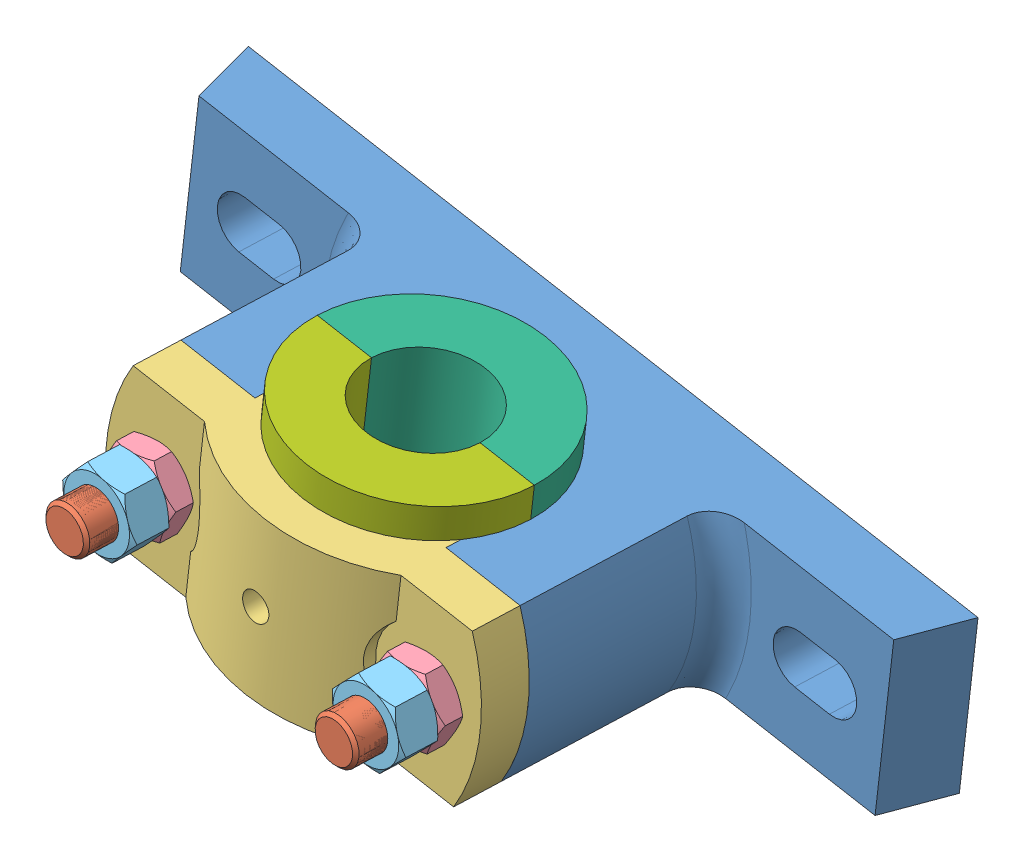
SolidWorks assembly PB, configuration Default. Lengths in mm.
Overall size (173.45 57.22 90.27).
10 component instances, 7 part files, 27 mates.
Components (placement in the parent):
- Body-PB-1: Body-PB [Default] at (22.8033 -109.1486 105.9036) x (-0.991123 0.125842 -0.042895) z (0.125431 0.992028 0.012142) size (168 55 36)
- Bolt-PB-1: Bolt-PB [Default] at (51.3093 -113.3846 157.5158) x (0.044081 0.006653 -0.999006) z (0.991123 -0.125842 0.042895) size (83.71 18 18)
- Cap-PB-1: Cap-PB [Default] at (18.5718 -127.303 150.4142) x (-0.991123 0.125842 -0.042895) z (0.125431 0.992028 0.012142) size (86 30 36)
- Bolt-PB-2: Bolt-PB [Default] at (-10.1402 -105.5824 154.8563) x (0.044081 0.006653 -0.999006) z (-0.125431 -0.992028 -0.012142) size (83.71 18 18)
- Lock Nut-PB-1: Lock Nut-PB [Default] at (50.6628 -113.4822 172.1687) x (0.942475 -0.33195 0.039376) z (-0.331358 -0.943273 -0.020903) size (17.57 5 17.08)
- M10-PB-1: M10-PB [Default] at (50.4424 -113.5154 177.1638) x (0.822368 -0.568026 0.032504) z (-0.567245 -0.822984 -0.030511) size (17.57 8 17.08)
- Lock Nut-PB-2: Lock Nut-PB [Default] at (-11.0072 -105.7132 174.5042) x (-0.086489 -0.996198 -0.010451) z (0.995277 -0.086863 0.043338) size (17.57 5 17.08)
- M10-PB-2: M10-PB [Default] at (-11.3599 -105.7665 182.4963) x (0.625284 -0.780076 0.022395) z (0.779152 0.625649 0.038547) size (17.57 8 17.08)
- Bearing Bottom Half-PB-2: Bearing Bottom Half-PB [Default] at (21.04 -109.4147 145.8638) x (-0.125431 -0.992028 -0.012142) z (0.044081 0.006653 -0.999006) size (50 50 25)
- Bearing Top Half-PB-2: Bearing Top Half-PB [Default] at (21.04 -109.4147 145.8638) x (-0.125431 -0.992028 -0.012142) z (-0.044081 -0.006653 0.999006) size (50 50 25)
Mates (geometry in assembly coordinates):
- Coincident8: coincident anti-aligned: plane of Body-PB-1 through (40.4547 -130.0597 149.586) normal (-0.044081 -0.006653 0.999006); plane of Cap-PB-1 through (44.9702 -94.3467 150.0231) normal (0.044081 0.006653 -0.999006)
- Coincident9: coincident anti-aligned: plane of Body-PB-1 through (-3.1547 -124.5227 147.6986) normal (-0.044081 -0.006653 0.999006); plane of Cap-PB-1 through (5.2978 -89.3095 148.3061) normal (0.044081 0.006653 -0.999006)
- Coincident10: coincident aligned: circle of Body-PB-1; circle of Cap-PB-1
- Coincident11: coincident aligned: circle of Body-PB-1; circle of Cap-PB-1
- Concentric2: concentric aligned: cylinder of Body-PB-1 through (53.1313 -113.1096 116.2244) axis (-0.044081 -0.006653 0.999006) radius 5.25; cylinder of Bolt-PB-1 through (48.6657 -113.7836 217.4295) axis (-0.044081 -0.006653 0.999006) radius 5
- Coincident13: coincident anti-aligned: plane of Body-PB-1 through (22.4065 -109.2085 114.8946) normal (0.044081 0.006653 -0.999006); plane of Bolt-PB-1 through (53.1313 -113.1096 116.2244) normal (-0.044081 -0.006653 0.999006)
- Concentric3: concentric aligned: cylinder of Body-PB-1 through (-8.3183 -105.3074 113.5649) axis (-0.044081 -0.006653 0.999006) radius 5.25; cylinder of Bolt-PB-2 through (-12.7839 -105.9814 214.77) axis (-0.044081 -0.006653 0.999006) radius 5
- Coincident14: coincident anti-aligned: plane of Body-PB-1 through (22.4065 -109.2085 114.8946) normal (0.044081 0.006653 -0.999006); plane of Bolt-PB-2 through (-8.3183 -105.3074 113.5649) normal (-0.044081 -0.006653 0.999006)
- Concentric4: concentric aligned: cylinder of Bolt-PB-1 through (48.6657 -113.7836 217.4295) axis (-0.044081 -0.006653 0.999006) radius 5; cylinder of Lock Nut-PB-1 through (50.8391 -113.4555 168.1727) axis (-0.044081 -0.006653 0.999006) radius 5
- Coincident15: coincident anti-aligned: plane of Cap-PB-1 through (44.6223 -94.572 172.0281) normal (-0.044081 -0.006653 0.999006); plane of Lock Nut-PB-1 through (50.6628 -113.4822 172.1687) normal (0.044081 0.006653 -0.999006)
- Concentric5: concentric aligned: cylinder of Bolt-PB-1 through (48.6657 -113.7836 217.4295) axis (-0.044081 -0.006653 0.999006) radius 5; cylinder of M10-PB-1 through (50.5305 -113.5021 175.1657) axis (-0.044081 -0.006653 0.999006) radius 5
- Coincident16: coincident anti-aligned: plane of Lock Nut-PB-1 through (50.4424 -113.5154 177.1638) normal (-0.044081 -0.006653 0.999006); plane of M10-PB-1 through (50.4424 -113.5154 177.1638) normal (0.044081 0.006653 -0.999006)
- Parallel5: parallel anti-aligned: plane of Body-PB-1 through (-16.9752 -94.1287 113.2574) normal (0.991123 -0.125842 0.042895); plane of Bolt-PB-2 through (-18.0146 -113.0498 105.0775) normal (-0.991123 0.125842 -0.042895)
- Concentric6: concentric anti-aligned: cylinder of Bolt-PB-2 through (-12.7839 -105.9814 214.77) axis (-0.044081 -0.006653 0.999006) radius 5; cylinder of Lock Nut-PB-2 through (-11.1835 -105.7399 178.5003) axis (0.044081 0.006653 -0.999006) radius 5
- Coincident18: coincident anti-aligned: plane of Cap-PB-1 through (-0.2308 -88.8771 170.0869) normal (-0.044081 -0.006653 0.999006); plane of Lock Nut-PB-2 through (-10.7868 -105.68 169.5092) normal (0.044081 0.006653 -0.999006)
- Concentric7: concentric anti-aligned: cylinder of Bolt-PB-2 through (-12.7839 -105.9814 214.77) axis (-0.044081 -0.006653 0.999006) radius 5; cylinder of M10-PB-2 through (-11.448 -105.7798 184.4943) axis (0.044081 0.006653 -0.999006) radius 5
- Concentric8: concentric anti-aligned: cylinder of Bolt-PB-2 through (-12.7839 -105.9814 214.77) axis (-0.044081 -0.006653 0.999006) radius 5; cylinder of M10-PB-2 through (-11.448 -105.7798 184.4943) axis (0.044081 0.006653 -0.999006) radius 5
- Coincident20: coincident anti-aligned: plane of Lock Nut-PB-2 through (-11.0072 -105.7132 174.5042) normal (-0.044081 -0.006653 0.999006); plane of M10-PB-2 through (-11.0072 -105.7132 174.5042) normal (0.044081 0.006653 -0.999006)
- Concentric11: concentric aligned: cylinder of Body-PB-1 through (22.1421 -109.2484 120.8887) axis (-0.044081 -0.006653 0.999006) radius 3; cylinder of Bearing Bottom Half-PB-2 through (22.0318 -109.265 123.3862) axis (-0.044081 -0.006653 0.999006) radius 3
- Concentric12: concentric aligned: cylinder of Body-PB-1 through (18.7823 -127.2712 145.6453) axis (0.125431 0.992028 0.012142) radius 19; cylinder of Bearing Bottom Half-PB-2 through (25.9255 -70.7759 146.3367) axis (0.125431 0.992028 0.012142) radius 17.5
- Coincident28: coincident anti-aligned: plane of Bearing Bottom Half-PB-2 through (21.04 -109.4147 145.8638) normal (-0.044081 -0.006653 0.999006); plane of Bearing Top Half-PB-2 through (21.04 -109.4147 145.8638) normal (0.044081 0.006653 -0.999006)
- Coincident29: coincident anti-aligned: plane of Bearing Bottom Half-PB-2 through (21.04 -109.4147 145.8638) normal (-0.044081 -0.006653 0.999006); plane of Bearing Top Half-PB-2 through (21.04 -109.4147 145.8638) normal (0.044081 0.006653 -0.999006)
- Parallel6: parallel anti-aligned: cylinder of Cap-PB-1 through (23.43 -91.5383 143.0854) axis (-0.125431 -0.992028 -0.012142) radius 19; cylinder of Bearing Top Half-PB-2 through (25.9255 -70.7759 146.3367) axis (0.125431 0.992028 0.012142) radius 17.5
- Coincident30: coincident anti-aligned: plane of Cap-PB-1 through (23.43 -91.5383 143.0854) normal (0.125431 0.992028 0.012142); plane of Bearing Top Half-PB-2 through (-1.4803 -88.4122 145.01) normal (-0.125431 -0.992028 -0.012142)
- Coincident31: coincident anti-aligned: plane of Cap-PB-1 through (18.9145 -127.2513 142.6483) normal (-0.125431 -0.992028 -0.012142); plane of Bearing Top Half-PB-2 through (-5.9958 -124.1252 144.5729) normal (0.125431 0.992028 0.012142)
- Concentric14: concentric aligned: cylinder of Cap-PB-1 through (20.467 -109.5012 158.8509) axis (-0.044081 -0.006653 0.999006) radius 1.5; cylinder of Bearing Top Half-PB-2 through (22.1641 -109.2451 120.3892) axis (-0.044081 -0.006653 0.999006) radius 2
- Parallel7: parallel anti-aligned: plane of Body-PB-1 through (44.4744 -101.9309 115.9169) normal (0.991123 -0.125842 0.042895); plane of Bolt-PB-1 through (45.6928 -102.9955 107.9556) normal (-0.991123 0.125842 -0.042895)
